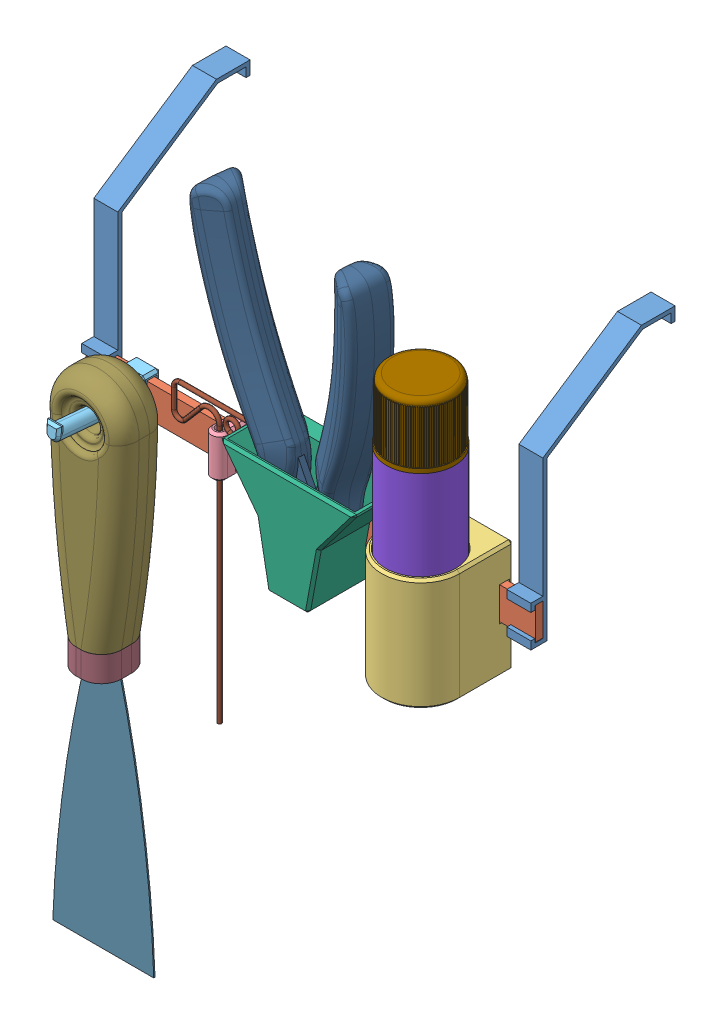
SolidWorks assembly Tool Caddy, configuration Default. Lengths in mm.
Overall size (178.2 295.65 90.24).
18 component instances, 14 part files, 22 mates.
Components (placement in the parent):
- Hanger-1: Hanger [Default] x (0 -1 0) z (1 0 0) size (89.54 57.16 9.53)
- Rail-2: Rail [Default] at (0 -69.8278 55.4741) x (1 0 0) z (0 1 0) size (178 3 12.7)
- Hanger-2: Hanger [Default] at (168.475 -0.1 0.1) x (0 -1 0) z (1 0 0) size (89.54 57.16 9.53)
- Glue Holder-1: Glue Holder [Default] at (148.8253 -101.1809 71.7148) size (30.88 44.45 36.84)
- Purge Tool Holder-1: Purge Tool Holder [Default] at (56.4777 -84.5122 59.046) size (6.35 16.67 11.91)
- Scrapper Holder-1: Scrapper Holder [Default] at (22.473 -84.5122 50.3148) x (0 0 1) z (0 -1 0) size (38.69 9.59 16.67)
- Snips Holder-1: Snips Holder [Default] at (100.2831 -76.1759 50.311) size (53.39 43.18 25.74)
- Glue Stick-1: Glue Stick [Default] at (148.8253 -99.5934 71.7148) size (27 103 27)
  - Glue Stick Base-1: Glue Stick Base [Default] at origin size (27 69.74 27)
  - Glue Stick Body-1: Glue Stick Body [Default] at (0 16 0) size (27 80 27)
  - Glue Stick Cap-1: Glue Stick Cap [Default] at (0 78 0) size (27 25 27)
- Snips-1: Snips [Default] at (100.2238 -80.0718 65.0073) x (0.986691 0.044979 0.15626) z (0.152756 0.072976 -0.985566) size (85.67 130.57 29.21)
- Purge Tool-1: Purge Tool [Default] at (56.4777 -169.0197 59.046) size (37.06 109.78 1.56)
- Scraper-1: Scraper [Default] at (19.8034 -76.3433 58.178) size (40 202.81 20.12)
  - Spartel_Complete_40mm.stp-1: Spartel_Complete_40mm.stp [Default] at origin size (40 202.81 20.12)
    - E5ndtag.stp-1: E5ndtag.stp [Default] at origin size (33.78 96.21 20.12)
    - Ring.stp-1: Ring.stp [Default] at (-9.0007 -76.0025 20) x (1 0 0) z (0 -1 0) size (18 20 10)
    - Blad.stp-1: Blad.stp [Default] at (-20.0007 -183.9751 10.25) x (1 0 0) z (0 0 -1) size (40 99.97 0.5)
Mates (geometry in assembly coordinates):
- Distance13: distance = 0.1 mm: plane of Hanger-1 through (9.525 -69.7278 52.3741) normal (0 0 1); plane of Rail-2 through (0 -69.8278 52.4741) normal (0 0 -1)
- Coincident5: coincident: plane of Hanger-1 through (0 0 0) normal (-1 0 0); plane of Rail-2 through (0 -69.8278 52.4741) normal (-1 0 0)
- Distance14: distance = 0.1 mm: plane of Hanger-1 through (9.525 -69.7278 55.5741) normal (0 -1 0); plane of Rail-2 through (0 -69.8278 52.4741) normal (0 1 0)
- Coincident11: coincident: plane of Rail-2 through (0 -69.8278 52.4741) normal (0 0 -1); plane of Hanger-2 through (178 -69.8278 52.4741) normal (0 0 1)
- Coincident8: coincident: plane of Rail-2 through (178 -69.8278 52.4741) normal (1 0 0); plane of Hanger-2 through (178 -0.1 0.1) normal (1 0 0)
- Coincident12: coincident: plane of Rail-2 through (0 -69.8278 52.4741) normal (0 1 0); plane of Hanger-2 through (178 -69.8278 55.6741) normal (0 -1 0)
- Distance1: distance = 0.3969 mm: plane of Glue Holder-1 through (133.3878 -69.4309 55.871) normal (0 0 -1); plane of Rail-2 through (0 -69.8278 55.4741) normal (0 0 1)
- Distance2: distance = 0.3969 mm: plane of Glue Holder-1 through (133.3878 -82.9247 55.871) normal (0 1 0); plane of Rail-2 through (0 -82.5278 52.4741) normal (0 -1 0)
- LimitDistance1: limit distance = 4.2122 mm: plane of Glue Holder-1 through (164.2628 -56.7309 50.3148) normal (1 0 0); plane of Hanger-2 through (168.475 -0.1 0.1) normal (-1 0 0)
- Distance8: distance = 0.3969 mm: plane of Purge Tool Holder-1 through (53.3027 -69.4309 55.871) normal (0 0 -1); plane of Rail-2 through (0 -69.8278 55.4741) normal (0 0 1)
- Distance9: distance = 0.3969 mm: plane of Purge Tool Holder-1 through (53.3027 -69.4309 51.9023) normal (0 -1 0); plane of Rail-2 through (0 -69.8278 52.4741) normal (0 1 0)
- LimitDistance3: limit distance = 108.8223 mm: plane of Purge Tool Holder-1 through (59.6527 -67.8434 50.3148) normal (1 0 0); plane of Hanger-2 through (168.475 -0.1 0.1) normal (-1 0 0)
- Distance11: distance = 0.3969 mm: plane of Scrapper Holder-1 through (16.885 -69.4309 55.871) normal (0 0 -1); plane of Rail-2 through (0 -69.8278 55.4741) normal (0 0 1)
- Distance12: distance = 0.3969 mm: plane of Scrapper Holder-1 through (16.885 -82.9247 55.871) normal (0 1 0); plane of Rail-2 through (0 -82.5278 52.4741) normal (0 -1 0)
- LimitDistance4: limit distance = 144.002 mm: plane of Scrapper Holder-1 through (24.473 -84.5122 50.3148) normal (1 0 0); plane of Hanger-2 through (168.475 -0.1 0.1) normal (-1 0 0)
- Distance15: distance = 0.3969 mm: plane of Snips Holder-1 through (73.0656 -69.4309 55.871) normal (0 0 -1); plane of Rail-2 through (0 -69.8278 55.4741) normal (0 0 1)
- Distance16: distance = 0.3969 mm: plane of Snips Holder-1 through (73.0656 -69.4309 51.901) normal (0 -1 0); plane of Rail-2 through (0 -69.8278 52.4741) normal (0 1 0)
- LimitDistance5: limit distance = 68.1919 mm: plane of Snips Holder-1 through (100.2831 -76.1759 50.311) normal (1 0 0); plane of Hanger-2 through (168.475 -0.1 0.1) normal (-1 0 0)
- Concentric1: concentric: cylinder of Glue Holder-1 through (148.8253 -56.7309 71.7148) axis (0 -1 0) radius 13.85; cylinder of Glue Stick-1/Glue Stick Body-1 through (148.8253 -31.3309 71.7148) axis (0 1 0) radius 13.5
- Coincident16: coincident: plane of Glue Holder-1 through (148.8253 -99.5934 71.7148) normal (0 1 0); circle of Glue Stick-1/Glue Stick Base-1
- Concentric2: concentric: cylinder of Purge Tool Holder-1 through (56.4777 -67.8434 59.046) axis (0 -1 0) radius 1.5875; cylinder of Purge Tool-1 through (56.4777 -169.0197 59.046) axis (0 1 0) radius 0.78
- Parallel1: parallel: plane of Rail-2 through (0 -69.8278 55.4741) normal (0 0 1); plane of Scraper-1/Spartel_Complete_40mm.stp-1/Blad.stp-1 through (19.8027 -217.0279 67.928) normal (0 0 -1)
